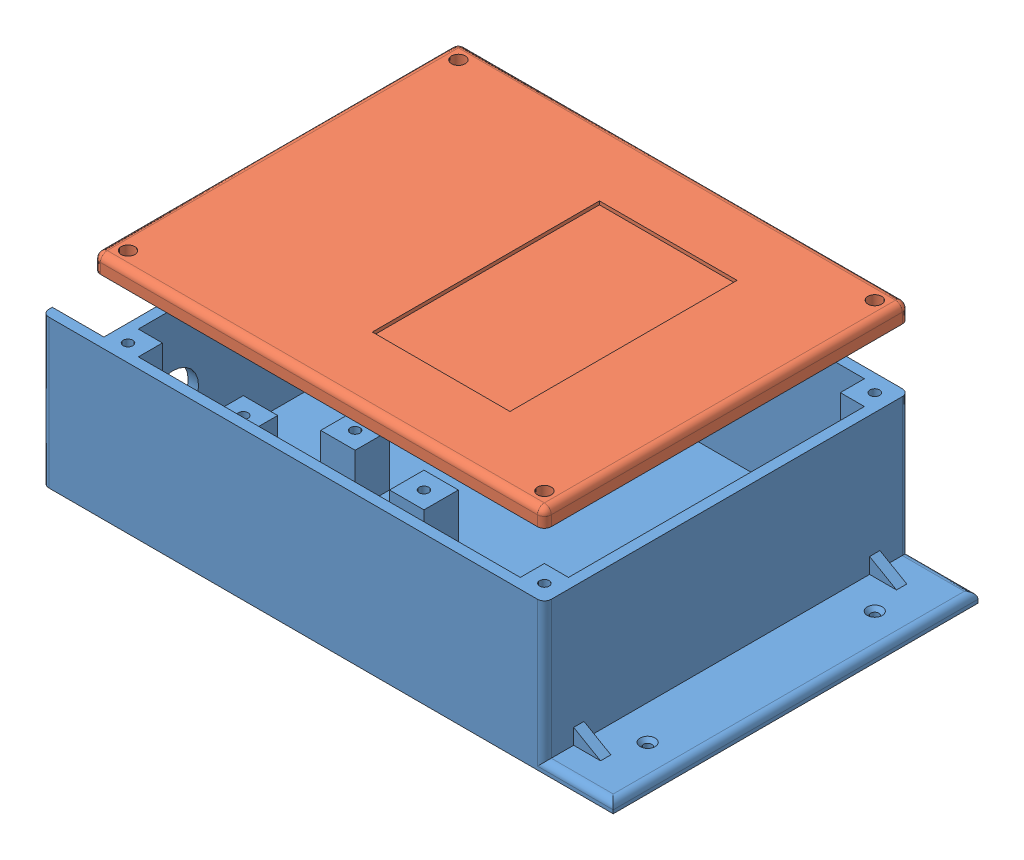
SolidWorks assembly Full Enclousre, configuration Default. Lengths in mm.
Overall size (166 66.25 106).
2 component instances, 2 part files, 2 mates.
Components (placement in the parent):
- Base-1: Base [Default] at (-11.7204 56.6243 186.6851) size (166 43 106)
- Base Cover-1: Base Cover [Default] at (3.2796 122.8779 80.6851) x (1 0 0) z (0 -1 0) size (131 106 6)
Mates (geometry in assembly coordinates):
- Coincident1: coincident aligned: plane of Base-1 through (-11.7204 99.6243 186.6851) normal (0 0 1); plane of Base Cover-1 through (3.2796 117.8779 186.6851) normal (0 0 1)
- Coincident2: coincident aligned: cylinder of Base-1 through (129.2796 89.6243 181.6851) axis (0 1 0) radius 1.4; circle of Base Cover-1
